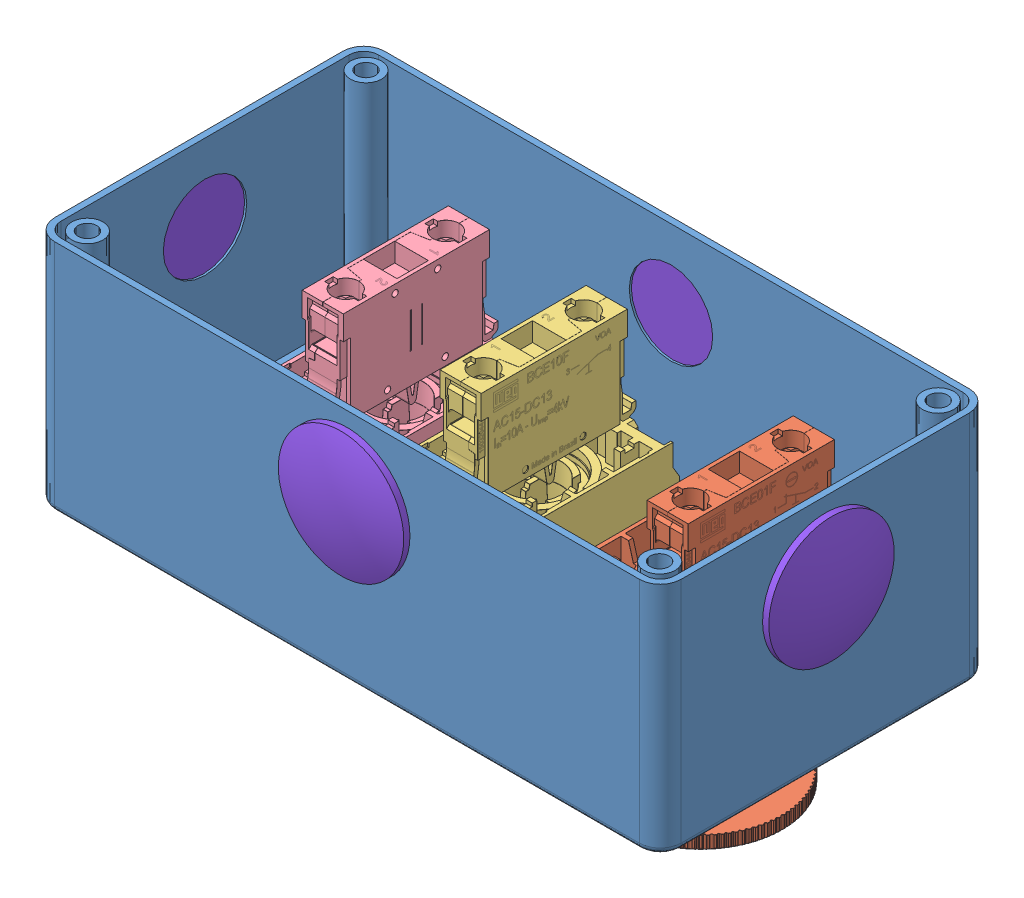
SolidWorks assembly botoeiras, configuration Default. Lengths in mm.
Overall size (158 84.15 87).
11 component instances, 8 part files, 27 mates.
Components (placement in the parent):
- caixa-botoes-1: caixa-botoes [Default] at (-6.3493 -13.6366 12.6149) size (150 56.2 79)
- emergencia-1: emergencia [Default] at (64.0763 18.5021 6.0881) x (1 0 0) z (0 -1 0) size (39.36 46.9 71.88)
- botoeira-red-2: botoeira-red [Default] at (18.2591 19.1084 7.9689) x (1 0 0) z (0 -1 0) size (30.5 46.9 61.5)
- botoeira-3: botoeira [Default] at (-63.9577 19.1084 17.261) x (-1 0 0) z (0 -1 0) size (30.5 46.9 61.5)
- placa liga-1: placa liga [Default] at (-39.3493 -13.3866 43.4649) x (1 0 0) z (0 -1 0) size (22.5 15 1)
- desliga-1: desliga [Default] at (-6.3493 -13.3866 43.4649) x (1 0 0) z (0 -1 0) size (22.5 15 1)
- emrg-1: emrg [Default] at (33.6507 -13.3866 43.4649) x (1 0 0) z (0 -1 0) size (22.5 15 1)
- botao-1: botao [Default] at (-80.5424 24.0634 17.6149) x (0 0.300013 -0.953935) z (0 0.953935 0.300013) size (30 5 30)
- botao-2: botao [Default] at (-6.4788 24.0634 -20.8851) x (-0.476054 -0.879416 0) z (0.879416 -0.476054 0) size (30 5 30)
- botao-3: botao [Default] at (67.4576 24.0634 17.6149) x (0 0.775785 -0.630997) z (0 -0.630997 -0.775785) size (30 5 30)
- botao-4: botao [Default] at (-6.4788 24.0634 56.1149) x (-0.776604 0.629989 0) z (0.629989 0.776604 0) size (30 5 30)
Mates (geometry in assembly coordinates):
- Coincident2: coincident: plane of caixa-botoes-1 through (-76.5424 -13.6366 -16.8851) normal (0 -1 0); circle of emergencia-1
- Concentric9: concentric: cylinder of caixa-botoes-1 through (-6.3493 42.5634 12.6149) axis (0 -1 0) radius 11.25; cylinder of botoeira-red-2 through (-6.3493 6.6434 12.6149) axis (0 1 0) radius 10.6
- Parallel3: parallel: plane of caixa-botoes-1 through (-7.9493 42.5634 0.3649) normal (0 0 1); plane of botoeira-red-2 through (-6.3493 6.6434 0.7149) normal (0 0 -1)
- Coincident8: coincident: plane of caixa-botoes-1 through (-76.5424 -13.6366 -16.8851) normal (0 -1 0); circle of botoeira-red-2
- Concentric11: concentric: cylinder of caixa-botoes-1 through (-39.3493 42.5634 12.6149) axis (0 -1 0) radius 11.25; cylinder of botoeira-3 through (-39.3493 6.6434 12.6149) axis (0 1 0) radius 10.6
- Coincident10: coincident: plane of caixa-botoes-1 through (-76.5424 -13.6366 -16.8851) normal (0 -1 0); circle of botoeira-3
- Concentric13: concentric: cylinder of caixa-botoes-1 through (33.6507 42.5634 12.6149) axis (0 -1 0) radius 11.25; cylinder of emergencia-1 through (33.6507 14.0134 12.6149) axis (0 1 0) radius 13.9
- Parallel4: parallel: plane of caixa-botoes-1 through (-80.0424 42.5634 -16.8851) normal (1 0 0); plane of botoeira-3 through (-34.4243 35.1453 12.6149) normal (1 0 0)
- Parallel5: parallel aligned: plane of emergencia-1 through (48.6507 -3.1107 32.5149) normal (1 0 0); plane of botoeira-red-2 through (-1.4243 35.1453 12.6149) normal (1 0 0)
- Coincident14: coincident: plane of caixa-botoes-1 through (-28.0993 -13.3866 50.9649) normal (0 -1 0); plane of placa liga-1 through (-50.5993 -13.3866 50.9649) normal (0 1 0)
- Coincident15: coincident: plane of caixa-botoes-1 through (-28.0993 -13.3866 35.9649) normal (-1 0 0); plane of placa liga-1 through (-28.0993 -13.8866 35.9649) normal (1 0 0)
- Coincident16: coincident: plane of caixa-botoes-1 through (-50.5993 -13.3866 35.9649) normal (0 0 1); plane of placa liga-1 through (-28.0993 -13.8866 35.9649) normal (0 0 -1)
- Parallel7: parallel: plane of caixa-botoes-1 through (4.9007 -13.3866 50.9649) normal (0 -1 0); plane of desliga-1 through (-17.5993 -13.3866 50.9649) normal (0 1 0)
- Coincident21: coincident: plane of caixa-botoes-1 through (-17.5993 -13.3866 35.9649) normal (0 0 1); plane of desliga-1 through (4.9007 -13.8866 35.9649) normal (0 0 -1)
- Coincident22: coincident: plane of caixa-botoes-1 through (-17.5993 -13.3866 35.9649) normal (1 0 0); plane of desliga-1 through (-17.5993 -13.8866 35.9649) normal (-1 0 0)
- Coincident24: coincident: plane of caixa-botoes-1 through (4.9007 -13.3866 50.9649) normal (0 -1 0); plane of desliga-1 through (-17.5993 -13.3866 50.9649) normal (0 1 0)
- Coincident25: coincident: plane of caixa-botoes-1 through (44.9007 -13.3866 35.9649) normal (0 0 1); plane of emrg-1 through (44.9007 -13.8866 35.9649) normal (0 0 -1)
- Coincident27: coincident: plane of caixa-botoes-1 through (22.4007 -13.3866 50.9649) normal (0 -1 0); plane of emrg-1 through (22.4007 -13.3866 50.9649) normal (0 1 0)
- Coincident28: coincident: plane of caixa-botoes-1 through (44.9007 -13.3866 35.9649) normal (-1 0 0); plane of emrg-1 through (44.9007 -13.8866 35.9649) normal (1 0 0)
- Concentric14: concentric: cylinder of caixa-botoes-1 through (68.4576 24.0634 17.6149) axis (-1 0 0) radius 10; cylinder of botao-1 through (-80.5424 24.0634 17.6149) axis (1 0 0) radius 10
- Coincident29: coincident: plane of caixa-botoes-1 through (-81.5424 42.5634 -16.8851) normal (-1 0 0); plane of botao-1 through (-81.5424 34.0634 17.6149) normal (1 0 0)
- Concentric15: concentric: cylinder of caixa-botoes-1 through (-6.4788 24.0634 57.1149) axis (0 0 -1) radius 10; cylinder of botao-2 through (-6.4788 24.0634 -20.8851) axis (0 0 1) radius 10
- Coincident30: coincident: plane of caixa-botoes-1 through (-76.5424 42.5634 -21.8851) normal (0 0 -1); plane of botao-2 through (-11.2394 15.2693 -21.8851) normal (0 0 1)
- Concentric16: concentric: cylinder of caixa-botoes-1 through (68.4576 24.0634 17.6149) axis (-1 0 0) radius 10; cylinder of botao-3 through (67.4576 24.0634 17.6149) axis (-1 0 0) radius 10
- Coincident31: coincident: plane of caixa-botoes-1 through (68.4576 42.5634 -16.8851) normal (1 0 0); plane of botao-3 through (68.4576 31.8213 11.305) normal (-1 0 0)
- Concentric17: concentric aligned: cylinder of caixa-botoes-1 through (-6.4788 24.0634 57.1149) axis (0 0 -1) radius 10; cylinder of botao-4 through (-6.4788 24.0634 56.1149) axis (0 0 -1) radius 10
- Coincident32: coincident anti-aligned: plane of caixa-botoes-1 through (-76.5424 42.5634 57.1149) normal (0 0 1); plane of botao-4 through (-14.2449 30.3633 57.1149) normal (0 0 -1)
